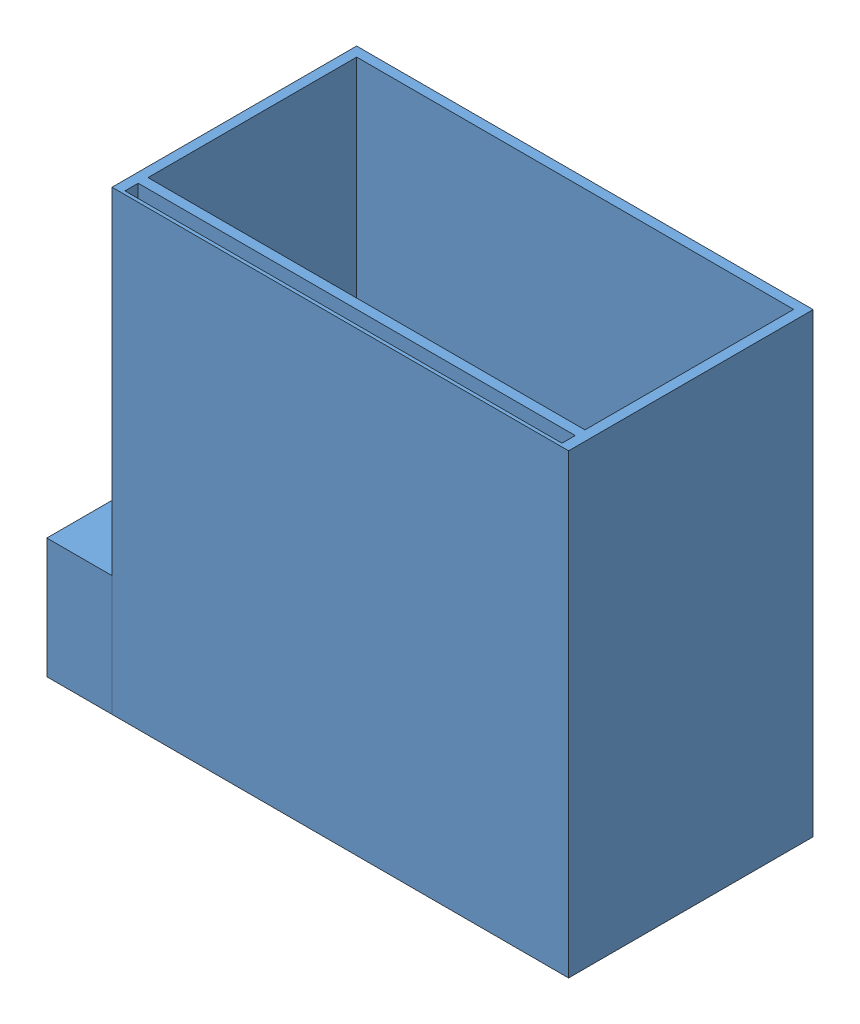
SolidWorks assembly TEGcontAssembly, configuration Default. Lengths in mm.
Overall size (160 140.27 75).
11 component instances, 3 part files, 34 mates.
Components (placement in the parent):
- TEGConteiner-1: TEGConteiner [Default] at (97.8257 -0.2698 133.2356) size (160 140 75)
- TEC1-12706-1: TEC1-12706 [00] at (9.089 115.54 147.2325) size (40.13 42 4)
- TEC1-12706-2: TEC1-12706 [00] at (51.0206 115.54 147.2325) size (40.13 42 4)
- TEC1-12706-4: TEC1-12706 [00] at (92.7946 115.54 147.2325) size (40.13 42 4)
- TEC1-12706-5: TEC1-12706 [00] at (9.089 71.4297 147.2325) size (40.13 42 4)
- TEC1-12706-6: TEC1-12706 [00] at (51.0206 71.4297 147.2325) size (40.13 42 4)
- TEC1-12706-7: TEC1-12706 [00] at (92.7946 71.4297 147.2325) size (40.13 42 4)
- TEC1-12706-9: TEC1-12706 [00] at (9.089 28.0855 147.2325) size (40.13 42 4)
- TEC1-12706-10: TEC1-12706 [00] at (51.0206 28.0855 147.2325) size (40.13 42 4)
- TEC1-12706-11: TEC1-12706 [00] at (92.7946 28.0855 147.2325) size (40.13 42 4)
- PowerBoost 500C - Full Res-3: PowerBoost 500C - Full Res [Default] at (-27.3111 20.4909 102.15) x (0 0 -1) z (0 -1 0) size (44.45 17.5 21.7)
Mates (geometry in assembly coordinates):
- Coincident3: coincident: plane of TEGConteiner-1 through (97.8257 139.7302 145.2325) normal (0 0 1); plane of TEC1-12706-4 through (92.7946 115.54 145.2325) normal (0 0 -1)
- Coincident9: coincident anti-aligned: plane of TEGConteiner-1 through (-19.0611 139.7302 133.2356) normal (-1 0 0); plane of PowerBoost 500C - Full Res-3 through (-19.0611 20.4909 102.15) normal (1 0 0)
- Coincident12: coincident: plane of TEGConteiner-1 through (97.8257 139.7302 145.2325) normal (0 0 1); plane of TEC1-12706-2 through (51.0206 115.54 145.2325) normal (0 0 -1)
- Coincident13: coincident: plane of TEGConteiner-1 through (97.8257 139.7302 145.2325) normal (0 0 1); plane of TEC1-12706-1 through (9.089 115.54 145.2325) normal (0 0 -1)
- Coincident16: coincident: plane of TEGConteiner-1 through (97.8257 139.7302 145.2325) normal (0 0 1); plane of TEC1-12706-5 through (9.089 71.4297 145.2325) normal (0 0 -1)
- Coincident17: coincident: plane of TEGConteiner-1 through (97.8257 139.7302 145.2325) normal (0 0 1); plane of TEC1-12706-6 through (51.0206 71.4297 145.2325) normal (0 0 -1)
- Coincident18: coincident: plane of TEGConteiner-1 through (97.8257 139.7302 145.2325) normal (0 0 1); plane of TEC1-12706-7 through (92.7946 71.4297 145.2325) normal (0 0 -1)
- Coincident19: coincident: plane of TEGConteiner-1 through (97.8257 139.7302 145.2325) normal (0 0 1); plane of TEC1-12706-9 through (9.089 28.0855 145.2325) normal (0 0 -1)
- Coincident20: coincident: plane of TEGConteiner-1 through (97.8257 139.7302 145.2325) normal (0 0 1); plane of TEC1-12706-10 through (51.0206 28.0855 145.2325) normal (0 0 -1)
- Coincident21: coincident: plane of TEGConteiner-1 through (97.8257 139.7302 145.2325) normal (0 0 1); plane of TEC1-12706-11 through (92.7946 28.0855 145.2325) normal (0 0 -1)
- Parallel3: parallel aligned: line of TEC1-12706-1 through (-10.911 135.54 149.2325) axis (1 0 0); line of TEC1-12706-2 through (31.0206 135.54 149.2325) axis (1 0 0)
- Parallel4: parallel aligned: line of TEC1-12706-6 through (31.0206 91.4297 149.2325) axis (1 0 0); line of TEC1-12706-7 through (72.7946 91.4297 149.2325) axis (1 0 0)
- Parallel5: parallel aligned: line of TEC1-12706-5 through (-10.911 91.4297 149.2325) axis (1 0 0); line of TEC1-12706-6 through (31.0206 91.4297 149.2325) axis (1 0 0)
- Parallel6: parallel aligned: line of TEC1-12706-9 through (-10.911 48.0855 149.2325) axis (1 0 0); line of TEC1-12706-10 through (31.0206 48.0855 149.2325) axis (1 0 0)
- Parallel7: parallel aligned: line of TEC1-12706-10 through (31.0206 48.0855 149.2325) axis (1 0 0); line of TEC1-12706-11 through (72.7946 48.0855 149.2325) axis (1 0 0)
- Parallel8: parallel: line of TEC1-12706-5 through (-10.911 51.4297 149.2325) axis (0 1 0); plane of TEC1-12706-9 through (-10.911 8.0855 148.4325) normal (-1 0 0)
- Parallel9: parallel aligned: line of TEC1-12706-1 through (-10.911 95.54 149.2325) axis (0 1 0); line of TEC1-12706-5 through (-10.911 51.4297 149.2325) axis (0 1 0)
- Parallel10: parallel aligned: line of TEC1-12706-2 through (31.0206 95.54 149.2325) axis (0 1 0); line of TEC1-12706-6 through (31.0206 51.4297 149.2325) axis (0 1 0)
- Parallel11: parallel aligned: line of TEC1-12706-6 through (31.0206 51.4297 149.2325) axis (0 1 0); line of TEC1-12706-10 through (31.0206 8.0855 149.2325) axis (0 1 0)
- Parallel12: parallel aligned: line of TEC1-12706-7 through (72.7946 51.4297 149.2325) axis (0 1 0); line of TEC1-12706-11 through (72.7946 8.0855 149.2325) axis (0 1 0)
- Parallel13: parallel aligned: line of TEC1-12706-4 through (72.7946 95.54 149.2325) axis (0 1 0); line of TEC1-12706-7 through (72.7946 51.4297 149.2325) axis (0 1 0)
- Coincident34: coincident aligned: line of TEC1-12706-2 through (31.0206 95.54 149.2325) axis (0 1 0); line of TEC1-12706-6 through (31.0206 51.4297 149.2325) axis (0 1 0)
- Coincident35: coincident aligned: line of TEC1-12706-1 through (-10.911 135.54 149.2325) axis (1 0 0); line of TEC1-12706-2 through (31.0206 135.54 149.2325) axis (1 0 0)
- Coincident36: coincident aligned: line of TEC1-12706-2 through (31.0206 135.54 149.2325) axis (1 0 0); line of TEC1-12706-4 through (72.7946 135.54 149.2325) axis (1 0 0)
- Coincident37: coincident aligned: line of TEC1-12706-5 through (-10.911 91.4297 149.2325) axis (1 0 0); line of TEC1-12706-6 through (31.0206 91.4297 149.2325) axis (1 0 0)
- Coincident38: coincident aligned: line of TEC1-12706-6 through (31.0206 91.4297 149.2325) axis (1 0 0); line of TEC1-12706-7 through (72.7946 91.4297 149.2325) axis (1 0 0)
- Coincident39: coincident aligned: line of TEC1-12706-9 through (-10.911 48.0855 149.2325) axis (1 0 0); line of TEC1-12706-10 through (31.0206 48.0855 149.2325) axis (1 0 0)
- Coincident40: coincident aligned: line of TEC1-12706-10 through (31.0206 48.0855 149.2325) axis (1 0 0); line of TEC1-12706-11 through (72.7946 48.0855 149.2325) axis (1 0 0)
- Coincident41: coincident aligned: line of TEC1-12706-5 through (-10.911 51.4297 149.2325) axis (0 1 0); line of TEC1-12706-9 through (-10.911 8.0855 149.2325) axis (0 1 0)
- Coincident42: coincident aligned: line of TEC1-12706-1 through (-10.911 95.54 149.2325) axis (0 1 0); line of TEC1-12706-5 through (-10.911 51.4297 149.2325) axis (0 1 0)
- Coincident43: coincident aligned: line of TEC1-12706-2 through (31.0206 95.54 149.2325) axis (0 1 0); line of TEC1-12706-6 through (31.0206 51.4297 149.2325) axis (0 1 0)
- Coincident44: coincident aligned: line of TEC1-12706-6 through (31.0206 51.4297 149.2325) axis (0 1 0); line of TEC1-12706-10 through (31.0206 8.0855 149.2325) axis (0 1 0)
- Coincident45: coincident aligned: line of TEC1-12706-4 through (72.7946 95.54 149.2325) axis (0 1 0); line of TEC1-12706-7 through (72.7946 51.4297 149.2325) axis (0 1 0)
- Coincident46: coincident aligned: line of TEC1-12706-7 through (72.7946 51.4297 149.2325) axis (0 1 0); line of TEC1-12706-11 through (72.7946 8.0855 149.2325) axis (0 1 0)
